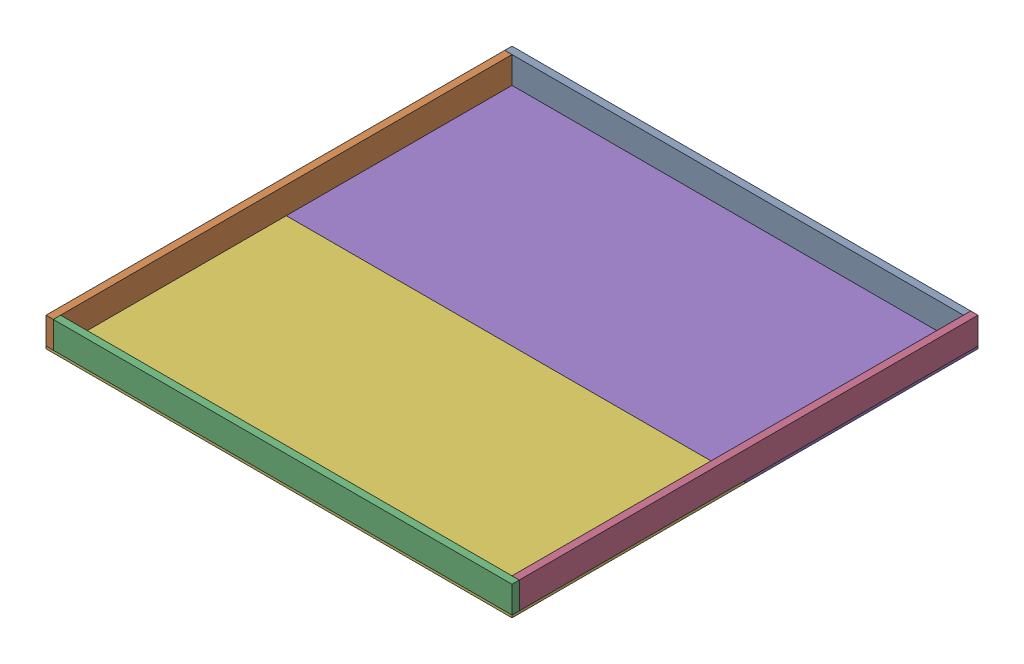
SolidWorks assembly Floor Assembly, configuration Default. Lengths in mm.
Overall size (2438.4 152.4 2438.4).
6 component instances, 2 part files, 18 mates.
Components (placement in the parent):
- 2x6-1: 2x6 [Default] at (-2438.4 152.4 -2400.3) x (0 -1 0) z (1 0 0) size (139.7 38.1 2400.3)
- 2x6-2: 2x6 [Default] at (-2438.4 152.4 -2400.3) x (0 -1 0) z (0 0 1) size (139.7 38.1 2400.3)
- 2x6-3: 2x6 [Default] at (-2400.3 152.4 0) x (0 -1 0) z (1 0 0) size (139.7 38.1 2400.3)
- 2x6-4: 2x6 [Default] at (-38.1 152.4 -2438.4) x (0 -1 0) z (0 0 1) size (139.7 38.1 2400.3)
- Sub Floor-1: Sub Floor [Default] at (-2438.4 0 -1219.2) size (2438.4 12.7 1219.2)
- Sub Floor-2: Sub Floor [Default] at (-2438.4 0 0) size (2438.4 12.7 1219.2)
Mates (geometry in assembly coordinates):
- Coincident31: coincident anti-aligned: plane of Plywood Base-1 through (-2438.4 12.7 -1219.2) normal (0 0 1); plane of Plywood Base-2 through (-2438.4 12.7 -1219.2) normal (0 0 -1)
- Coincident32: coincident aligned: plane of Plywood Base-1 through (-2438.4 12.7 -1219.2) normal (-1 0 0); plane of Plywood Base-2 through (-2438.4 12.7 0) normal (-1 0 0)
- Coincident33: coincident aligned: plane of Plywood Base-1 through (-2438.4 0 -1219.2) normal (0 -1 0); plane of Plywood Base-2 through (-2438.4 0 0) normal (0 -1 0)
- Coincident34: coincident anti-aligned: plane of Plywood Base-1 through (-2438.4 0 -1219.2) normal (0 -1 0)
- Coincident36: coincident aligned: plane of Plywood Base-1 through (0 12.7 -1219.2) normal (1 0 0)
- Coincident37: coincident aligned: plane of Plywood Base-2 through (-2438.4 12.7 0) normal (0 0 1)
- Coincident38: coincident aligned: plane of 2 by 6-3 through (0 12.7 0) normal (1 0 0); plane of 2 by 6-4 through (0 152.4 0) normal (1 0 0)
- Coincident39: coincident aligned: plane of 2 by 6-3 through (38.1 152.4 0) normal (0 1 0); plane of 2 by 6-4 through (-38.1 152.4 0) normal (0 1 0)
- Coincident40: coincident anti-aligned: plane of 2 by 6-3 through (38.1 152.4 -38.1) normal (0 0 -1); plane of 2 by 6-4 through (-38.1 12.7 -38.1) normal (0 0 1)
- Coincident41: coincident anti-aligned: plane of 2 by 6-1 through (-38.1 12.7 -2400.3) normal (1 0 0); plane of 2 by 6-4 through (-38.1 152.4 0) normal (-1 0 0)
- Coincident42: coincident aligned: plane of 2 by 6-1 through (0 152.4 -2400.3) normal (0 1 0); plane of 2 by 6-4 through (-38.1 152.4 0) normal (0 1 0)
- Coincident43: coincident aligned: plane of 2 by 6-1 through (0 152.4 -2438.4) normal (0 0 -1); plane of 2 by 6-4 through (-38.1 152.4 -2438.4) normal (0 0 -1)
- Coincident44: coincident anti-aligned: plane of 2 by 6-1 through (0 152.4 -2400.3) normal (0 0 1); plane of 2 by 6-2 through (-2438.4 152.4 -2400.3) normal (0 0 -1)
- Coincident45: coincident aligned: plane of 2 by 6-1 through (0 152.4 -2400.3) normal (0 1 0); plane of 2 by 6-2 through (-2438.4 152.4 38.1) normal (0 1 0)
- Coincident46: coincident aligned: plane of 2 by 6-1 through (-2438.4 152.4 -2400.3) normal (-1 0 0); plane of 2 by 6-2 through (-2438.4 152.4 38.1) normal (-1 0 0)
- Coincident47: coincident anti-aligned: plane of 2 by 6-2 through (-2438.4 12.7 38.1) normal (0 -1 0); plane of Plywood Base-2 through (-2438.4 12.7 0) normal (0 1 0)
- Coincident48: coincident aligned: plane of 2 by 6-3 through (38.1 152.4 0) normal (0 0 1); plane of Plywood Base-2 through (-2438.4 12.7 0) normal (0 0 1)
- Coincident49: coincident aligned: plane of 2 by 6-2 through (-2438.4 152.4 38.1) normal (-1 0 0); plane of Plywood Base-2 through (-2438.4 12.7 0) normal (-1 0 0)
